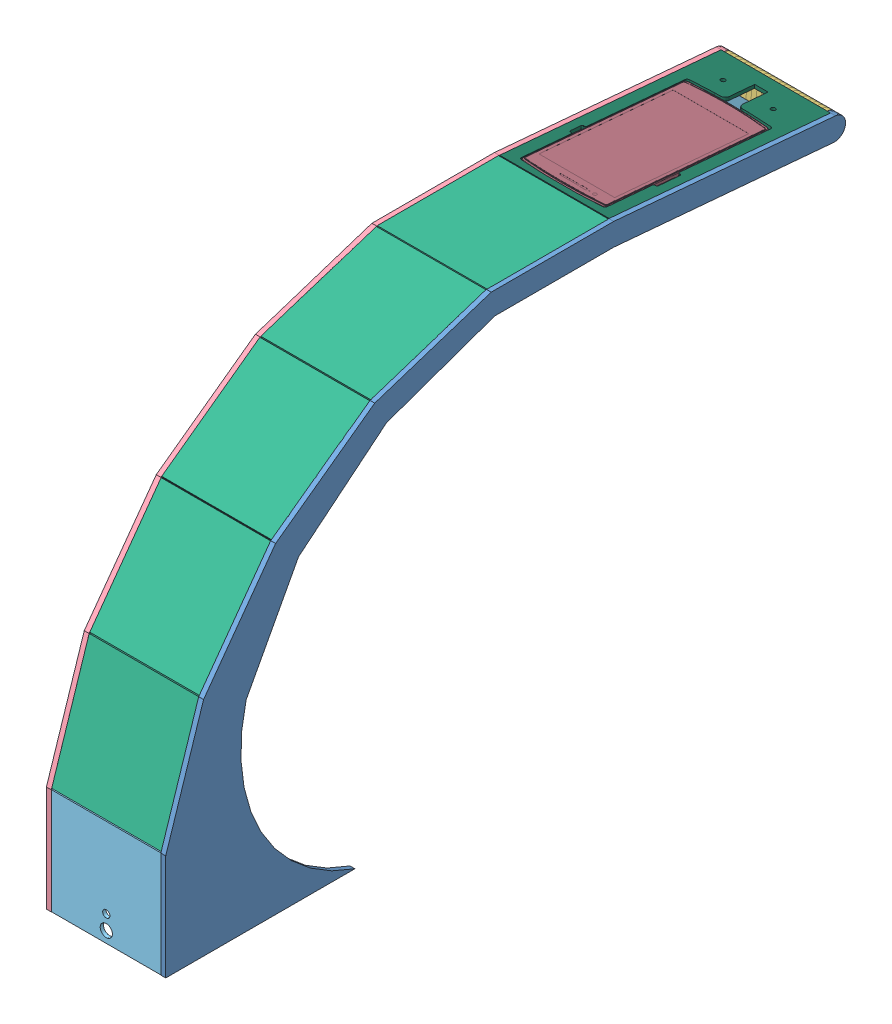
SolidWorks assembly Assem1, configuration Default. Lengths in mm.
Overall size (107.2 389.46 611.71).
44 component instances, 16 part files, 66 mates.
Components (placement in the parent):
- Outer Edge v2-1: Outer Edge v2 [Default] at (211.152 225.8443 792.324) size (7.4 387.43 610.87)
- phone support-1: phone support [Default] at (152.1683 492.2276 185.5195) x (1 0 0) z (0 0.087156 0.996195) size (98.5 3.2 10)
- phone support-2: phone support [Default] at (152.1683 496.7484 240.6352) x (1 0 0) z (0 0.087156 0.996195) size (98.5 3.2 10)
- phone support-3: phone support [Default] at (152.1683 504.6448 330.8905) x (1 0 0) z (0 0.087156 0.996195) size (98.5 3.2 10)
- Rounded piece v1-1: Rounded piece v1 [Default] at (203.752 493.2491 178.8372) x (-1 0 0) z (0 -0.087156 -0.996195) size (4.4 20 20)
- Rounded piece v1-2: Rounded piece v1 [Default] at (199.352 493.2491 178.8372) x (-1 0 0) z (0 -0.087156 -0.996195) size (4.4 20 20)
- Rounded piece v1-3: Rounded piece v1 [Default] at (194.952 493.2491 178.8372) x (-1 0 0) z (0 -0.087156 -0.996195) size (4.4 20 20)
- Rounded piece v1-4: Rounded piece v1 [Default] at (190.552 493.2491 178.8372) x (-1 0 0) z (0 -0.087156 -0.996195) size (4.4 20 20)
- Rounded piece v1-5: Rounded piece v1 [Default] at (186.152 493.2491 178.8372) x (-1 0 0) z (0 -0.087156 -0.996195) size (4.4 20 20)
- Rounded piece v1-6: Rounded piece v1 [Default] at (181.752 493.2491 178.8372) x (-1 0 0) z (0 -0.087156 -0.996195) size (4.4 20 20)
- Rounded piece v1-7: Rounded piece v1 [Default] at (177.352 493.2491 178.8372) x (-1 0 0) z (0 -0.087156 -0.996195) size (4.4 20 20)
- Rounded piece v1-8: Rounded piece v1 [Default] at (172.952 493.2491 178.8372) x (-1 0 0) z (0 -0.087156 -0.996195) size (4.4 20 20)
- Rounded piece v1-9: Rounded piece v1 [Default] at (168.552 493.2491 178.8372) x (-1 0 0) z (0 -0.087156 -0.996195) size (4.4 20 20)
- Rounded piece v1-10: Rounded piece v1 [Default] at (164.152 493.2491 178.8372) x (-1 0 0) z (0 -0.087156 -0.996195) size (4.4 20 20)
- Rounded piece v1-11: Rounded piece v1 [Default] at (159.752 493.2491 178.8372) x (-1 0 0) z (0 -0.087156 -0.996195) size (4.4 20 20)
- Rounded piece v1-12: Rounded piece v1 [Default] at (155.352 493.2491 178.8372) x (-1 0 0) z (0 -0.087156 -0.996195) size (4.4 20 20)
- Rounded piece v1-13: Rounded piece v1 [Default] at (150.952 493.2491 178.8372) x (-1 0 0) z (0 -0.087156 -0.996195) size (4.4 20 20)
- Rounded piece v1-14: Rounded piece v1 [Default] at (146.552 493.2491 178.8372) x (-1 0 0) z (0 -0.087156 -0.996195) size (4.4 20 20)
- Rounded piece v1-15: Rounded piece v1 [Default] at (142.152 493.2491 178.8372) x (-1 0 0) z (0 -0.087156 -0.996195) size (4.4 20 20)
- Rounded piece v1-16: Rounded piece v1 [Default] at (137.752 493.2491 178.8372) x (-1 0 0) z (0 -0.087156 -0.996195) size (4.4 20 20)
- Rounded piece v1-17: Rounded piece v1 [Default] at (133.352 493.2491 178.8372) x (-1 0 0) z (0 -0.087156 -0.996195) size (4.4 20 20)
- Rounded piece v1-18: Rounded piece v1 [Default] at (128.952 493.2491 178.8372) x (-1 0 0) z (0 -0.087156 -0.996195) size (4.4 20 20)
- Rounded piece v1-19: Rounded piece v1 [Default] at (124.552 493.2491 178.8372) x (-1 0 0) z (0 -0.087156 -0.996195) size (4.4 20 20)
- Rounded piece v1-20: Rounded piece v1 [Default] at (120.152 493.2491 178.8372) x (-1 0 0) z (0 -0.087156 -0.996195) size (4.4 20 20)
- Rounded piece v1-21: Rounded piece v1 [Default] at (115.752 493.2491 178.8372) x (-1 0 0) z (0 -0.087156 -0.996195) size (4.4 20 20)
- MirrorOuter Edge v2-5: MirrorOuter Edge v2 [Default] at (103.952 225.8443 792.324) x (-1 0 0) z (0 0 -1) size (7.4 387.43 610.87)
- top 1-1: top 1 [Default] at (128.85 126.9295 779.5123) x (0 -1 0) z (1 0 0) size (95 3 98.8)
- top 2-3-4-5-6-1: top 2-3-4-5-6 [Default] at (186.254 289.8492 756.5132) x (0 -0.951057 0.309017) z (-1 0 0) size (109 3 98.8)
- top 2-3-4-5-6-2: top 2-3-4-5-6 [Default] at (186.254 369.4632 719.1072) x (0 0.809017 -0.587785) z (-1 0 0) size (109 3 98.8)
- top 2-3-4-5-6-3: top 2-3-4-5-6 [Default] at (186.254 458.0212 626.2249) x (0 -0.587785 0.809017) z (-1 0 0) size (109 3 98.8)
- top 2-3-4-5-6-4: top 2-3-4-5-6 [Default] at (128.85 497.6699 548.2656) x (0 0.309017 -0.951057) z (1 0 0) size (109 3 98.8)
- top 2-3-4-5-6-5: top 2-3-4-5-6 [Default] at (128.85 517.6422 442.4332) x (0 0 -1) z (1 0 0) size (109 3 98.8)
- bottom 1-2: bottom 1 [Default] at (128.85 175.7778 702.9849) x (0 0.937746 0.347321) z (1 0 0) size (102 3 98.8)
- bottom 2-2: bottom 2 [Default] at (186.254 273.9501 717.8573) x (0 0.982743 -0.184975) z (-1 0 0) size (85.2 3 98.8)
- bottom 3-1: bottom 3 [Default] at (128.85 363.8422 683.7778) x (0 -0.880634 0.473798) z (1 0 0) size (99.7 3 98.8)
- bottom 4-1: bottom 4 [Default] at (128.85 429.4876 625.9213) x (0 0.633634 -0.773633) z (1 0 0) size (102.06 3 98.8)
- bottom 5-1: bottom 5 [Default] at (128.85 480.8727 539.4632) x (0 0.33437 -0.942442) z (1 0 0) size (103 3 98.8)
- bottom 6-1: bottom 6 [Default] at (186.254 500.5527 421.526) x (0 -0.000295 1) z (-1 0 0) size (106.88 3 98.8)
- ONEPLUSONE.catpart-1: ONEPLUSONE.catpart [Default] at (157.552 507.1829 218.7748) x (-1 0 0) z (0 0.996195 -0.087156) size (76.5 179.63 10.19)
- bottom 7-1: bottom 7 [Default] at (136.6559 495.3125 317.1592) x (0 -0.087156 -0.996195) z (1 0 0) size (198.26 3 98.8)
- top phone insert-1: top phone insert [Default] at (134.9798 513.2564 327.2058) x (0 -0.087156 -0.996195) z (1 0 0) size (199.69 3 98.8)
- phone support-4: phone support [Default] at (152.2683 163.411 758.2766) size (98.5 3.2 10)
- phone support-5: phone support [Default] at (152.2683 221.787 733.2489) x (1 0 0) z (0 0.937746 0.347321) size (98.5 3.2 10)
- Weight Container v1-1: Weight Container v1 [Default] at (194.352 213.6689 753.652) x (0 0 1) z (0 -1 0) size (62 83 163.96)
Mates (geometry in assembly coordinates):
- Coincident3: coincident: plane of Outer Edge v2-1 through (206.752 493.2491 178.8372) normal (-1 0 0); plane of phone support-1 through (206.752 494.4072 173.7168) normal (1 0 0)
- Width1: width: plane of phone support-1 through (108.252 495.2788 183.6787) normal (0 0.087156 0.996195); plane of phone support-1 through (108.252 494.4072 173.7168) normal (0 -0.087156 -0.996195); plane of Outer Edge v2-1 through (203.752 495.5041 183.9601) normal (0 -0.087156 -0.996195); plane of Outer Edge v2-1 through (203.752 494.5803 173.4005) normal (0 0.087156 0.996195)
- Width2: width: plane of phone support-1 through (152.1683 495.4154 185.2406) normal (0 0.996195 -0.087156); plane of phone support-1 through (152.1683 492.2276 185.5195) normal (0 -0.996195 0.087156); plane of Outer Edge v2-1 through (203.752 494.5803 173.4005) normal (0 -0.996195 0.087156); plane of Outer Edge v2-1 through (203.752 490.994 173.7142) normal (0 0.996195 -0.087156)
- Coincident6: coincident: plane of Outer Edge v2-1 through (206.752 493.2491 178.8372) normal (-1 0 0); plane of phone support-2 through (206.752 498.9281 228.8325) normal (1 0 0)
- Width3: width: plane of phone support-2 through (108.252 499.7996 238.7944) normal (0 0.087156 0.996195); plane of phone support-2 through (108.252 498.9281 228.8325) normal (0 -0.087156 -0.996195); plane of Outer Edge v2-1 through (203.752 500.025 239.0759) normal (0 -0.087156 -0.996195); plane of Outer Edge v2-1 through (203.752 499.1012 228.5162) normal (0 0.087156 0.996195)
- Width4: width: plane of phone support-2 through (152.1683 499.9363 240.3563) normal (0 0.996195 -0.087156); plane of phone support-2 through (152.1683 496.7484 240.6352) normal (0 -0.996195 0.087156); plane of Outer Edge v2-1 through (203.752 499.1012 228.5162) normal (0 -0.996195 0.087156); plane of Outer Edge v2-1 through (203.752 495.5149 228.83) normal (0 0.996195 -0.087156)
- Coincident7: coincident: plane of Outer Edge v2-1 through (206.752 493.2491 178.8372) normal (-1 0 0); plane of phone support-3 through (206.752 506.8244 319.0877) normal (1 0 0)
- Width5: width: plane of phone support-3 through (108.252 506.8244 319.0877) normal (0 -0.087156 -0.996195); plane of phone support-3 through (108.252 507.6959 329.0497) normal (0 0.087156 0.996195); plane of Outer Edge v2-1 through (203.752 507.9213 329.3311) normal (0 -0.087156 -0.996195); plane of Outer Edge v2-1 through (203.752 506.9975 318.7714) normal (0 0.087156 0.996195)
- Width6: width: plane of phone support-3 through (152.1683 507.8326 330.6116) normal (0 0.996195 -0.087156); plane of phone support-3 through (152.1683 504.6448 330.8905) normal (0 -0.996195 0.087156); plane of Outer Edge v2-1 through (203.752 503.4112 319.0852) normal (0 0.996195 -0.087156); plane of Outer Edge v2-1 through (203.752 506.9975 318.7714) normal (0 -0.996195 0.087156)
- Coincident8: coincident: plane of Outer Edge v2-1 through (203.752 493.2491 178.8372) normal (-1 0 0); plane of Rounded piece v1-1 through (203.752 493.2491 178.8372) normal (1 0 0)
- Width7: width: plane of phone support-1 through (152.1683 495.4154 185.2406) normal (0 0.996195 -0.087156); plane of phone support-1 through (152.1683 492.2276 185.5195) normal (0 -0.996195 0.087156); plane of Rounded piece v1-1 through (199.352 494.7621 173.1838) normal (0 -0.996195 0.087156); plane of Rounded piece v1-1 through (199.352 490.7773 173.5324) normal (0 0.996195 -0.087156)
- Width8: width: plane of phone support-1 through (108.252 494.4072 173.7168) normal (0 -0.087156 -0.996195); plane of phone support-1 through (108.252 495.2788 183.6787) normal (0 0.087156 0.996195); plane of Rounded piece v1-1 through (199.352 494.7621 173.1838) normal (0 0.087156 0.996195); plane of Rounded piece v1-1 through (199.352 495.7208 184.142) normal (0 -0.087156 -0.996195)
- Width9: width: plane of MirrorOuter Edge v2-5 through (108.352 493.2491 178.8372) normal (1 0 0); plane of Outer Edge v2-1 through (206.752 493.2491 178.8372) normal (-1 0 0); plane of top 1-1 through (108.152 228.211 776.5123) normal (-1 0 0); plane of top 1-1 through (206.952 228.211 776.5123) normal (1 0 0)
- Coincident10: coincident: plane of top 1-1 through (108.152 133.211 776.5123) normal (0 -1 0); line of MirrorOuter Edge v2-5 through (108.352 133.211 779.7088) axis (0 0 -1)
- Width10: width: plane of MirrorOuter Edge v2-5 through (108.352 493.2491 178.8372) normal (1 0 0); plane of Outer Edge v2-1 through (206.752 493.2491 178.8372) normal (-1 0 0); plane of top 2-3-4-5-6-1 through (108.152 332.8905 745.6826) normal (-1 0 0); plane of top 2-3-4-5-6-1 through (206.952 332.8905 745.6826) normal (1 0 0)
- Coincident11: coincident: plane of MirrorOuter Edge v2-5 through (111.352 331.5022 742.9793) normal (0 0.309017 0.951057); plane of top 2-3-4-5-6-1 through (186.254 289.8492 756.5132) normal (0 -0.309017 -0.951057)
- Coincident13: coincident: plane of MirrorOuter Edge v2-5 through (111.352 228.2983 776.5123) normal (0 0 1); plane of top 1-1 through (128.85 126.9295 776.5123) normal (0 0 -1)
- Coincident14: coincident: point of MirrorOuter Edge v2-5; plane of top 2-3-4-5-6-1 through (206.952 229.2253 779.3654) normal (0 -0.951057 0.309017)
- Width11: width: plane of MirrorOuter Edge v2-5 through (108.352 493.2491 178.8372) normal (1 0 0); plane of Outer Edge v2-1 through (206.752 493.2491 178.8372) normal (-1 0 0); plane of top 2-3-4-5-6-2 through (108.152 331.8753 742.7082) normal (-1 0 0); plane of top 2-3-4-5-6-2 through (206.952 331.8753 742.7082) normal (1 0 0)
- Coincident15: coincident: plane of MirrorOuter Edge v2-5 through (111.352 419.7772 678.8438) normal (0 0.587785 0.809017); plane of top 2-3-4-5-6-2 through (186.254 367.6999 716.6801) normal (0 -0.587785 -0.809017)
- Coincident18: coincident: line of top 2-3-4-5-6-1 through (206.952 331.9634 742.8294) axis (-1 0 0); plane of top 2-3-4-5-6-2 through (206.952 331.8753 742.7082) normal (0 -0.809017 0.587785)
- Width12: width: plane of MirrorOuter Edge v2-5 through (103.952 493.2491 178.8372) normal (-1 0 0); plane of Outer Edge v2-1 through (211.152 493.2491 178.8372) normal (1 0 0); plane of top 2-3-4-5-6-3 through (206.952 486.4763 592.1637) normal (1 0 0); plane of top 2-3-4-5-6-3 through (108.152 486.4763 592.1637) normal (-1 0 0)
- Coincident19: coincident: plane of MirrorOuter Edge v2-5 through (108.352 421.9331 680.9997) normal (0 0.809017 0.587785); plane of top 2-3-4-5-6-3 through (186.254 460.4482 627.9883) normal (0 0.809017 0.587785)
- Coincident20: coincident: line of top 2-3-4-5-6-2 through (108.152 420.0582 678.6396) axis (1 0 0); plane of top 2-3-4-5-6-3 through (206.952 422.4077 680.3466) normal (0 -0.587785 0.809017)
- Width13: width: plane of Outer Edge v2-1 through (211.152 493.2491 178.8372) normal (1 0 0); plane of MirrorOuter Edge v2-5 through (103.952 493.2491 178.8372) normal (-1 0 0); plane of top 2-3-4-5-6-4 through (108.152 486.8393 591.3069) normal (-1 0 0); plane of top 2-3-4-5-6-4 through (206.952 486.8393 591.3069) normal (1 0 0)
- Coincident21: coincident: plane of MirrorOuter Edge v2-5 through (108.352 486.6294 591.953) normal (0 0.951057 0.309017); plane of top 2-3-4-5-6-4 through (128.85 500.523 549.1927) normal (0 0.951057 0.309017)
- Coincident22: coincident: line of top 2-3-4-5-6-3 through (206.952 484.0492 590.4004) axis (-1 0 0); plane of top 2-3-4-5-6-4 through (108.152 486.8393 591.3069) normal (0 -0.309017 0.951057)
- Width14: width: plane of Outer Edge v2-1 through (211.152 493.2491 178.8372) normal (1 0 0); plane of MirrorOuter Edge v2-5 through (103.952 493.2491 178.8372) normal (-1 0 0); plane of top 2-3-4-5-6-5 through (108.152 520.6422 486.7147) normal (-1 0 0); plane of top 2-3-4-5-6-5 through (206.952 520.6422 486.7147) normal (1 0 0)
- Coincident23: coincident: plane of Outer Edge v2-1 through (206.752 520.6422 487.2723) normal (0 1 0); plane of top 2-3-4-5-6-5 through (128.85 520.6422 442.4332) normal (0 1 0)
- Coincident25: coincident: line of top 2-3-4-5-6-4 through (206.952 517.669 486.7147) axis (-1 0 0); plane of top 2-3-4-5-6-5 through (108.152 520.6422 486.7147) normal (0 0 1)
- Width16: width: plane of Outer Edge v2-1 through (211.152 493.2491 178.8372) normal (1 0 0); plane of MirrorOuter Edge v2-5 through (103.952 493.2491 178.8372) normal (-1 0 0); plane of bottom 1-2 through (108.152 133.211 690.4182) normal (-1 0 0); plane of bottom 1-2 through (206.952 133.211 690.4182) normal (1 0 0)
- Coincident26: coincident: plane of Outer Edge v2-1 through (203.752 133.211 690.4182) normal (0 0.347321 -0.937746); plane of bottom 1-2 through (128.85 174.7359 705.7981) normal (0 -0.347321 0.937746)
- Coincident27: coincident: line of MirrorOuter Edge v2-5 through (111.352 133.211 690.4182) axis (-1 0 0); plane of bottom 1-2 through (108.152 133.211 690.4182) normal (0 -0.937746 -0.347321)
- Width20: width: plane of Outer Edge v2-1 through (211.152 493.2491 178.8372) normal (1 0 0); plane of MirrorOuter Edge v2-5 through (103.952 493.2491 178.8372) normal (-1 0 0); plane of bottom 2-2 through (206.952 229.8778 723.1) normal (1 0 0); plane of bottom 2-2 through (108.152 229.8778 723.1) normal (-1 0 0)
- Coincident31: coincident: plane of MirrorOuter Edge v2-5 through (111.352 229.7546 726.1759) normal (0 -0.184975 -0.982743); plane of bottom 2-2 through (186.254 273.9501 717.8573) normal (0 0.184975 0.982743)
- Coincident36: coincident: plane of bottom 1-2 through (108.152 228.8611 725.845) normal (0 0.937746 0.347321); line of bottom 2-2 through (206.952 229.8778 723.1) axis (-1 0 0)
- Width21: width: plane of Outer Edge v2-1 through (211.152 493.2491 178.8372) normal (1 0 0); plane of MirrorOuter Edge v2-5 through (103.952 493.2491 178.8372) normal (-1 0 0); plane of bottom 3-1 through (108.152 401.4167 660.1554) normal (-1 0 0); plane of bottom 3-1 through (206.952 401.4167 660.1554) normal (1 0 0)
- Coincident37: coincident: plane of bottom 3-1 through (128.85 363.8422 683.7778) normal (0 0.473798 0.880634); plane of MirrorOuter Edge v2-5 through (111.352 314.7856 710.1711) normal (0 -0.473798 -0.880634)
- Coincident38: coincident: plane of bottom 2-2 through (206.952 313.6075 707.3402) normal (0 0.982743 -0.184975); line of bottom 3-1 through (206.952 313.6175 707.393) axis (-1 0 0)
- Width22: width: plane of Outer Edge v2-1 through (211.152 493.2491 178.8372) normal (1 0 0); plane of MirrorOuter Edge v2-5 through (103.952 493.2491 178.8372) normal (-1 0 0); plane of bottom 4-1 through (108.152 403.7503 662.0799) normal (-1 0 0); plane of bottom 4-1 through (206.952 403.7503 662.0799) normal (1 0 0)
- Coincident39: coincident: plane of bottom 3-1 through (108.152 401.4167 660.1554) normal (0 0.880634 -0.473798); line of bottom 4-1 through (108.152 401.4294 660.179) axis (1 0 0)
- Coincident40: coincident: plane of MirrorOuter Edge v2-5 through (111.352 403.4184 662.485) normal (0 -0.773633 -0.633634); plane of bottom 4-1 through (128.85 431.8085 627.8222) normal (0 0.773633 0.633634)
- Width23: width: plane of Outer Edge v2-1 through (211.152 493.2491 178.8372) normal (1 0 0); plane of MirrorOuter Edge v2-5 through (103.952 493.2491 178.8372) normal (-1 0 0); plane of bottom 5-1 through (108.152 468.8936 582.1991) normal (-1 0 0); plane of bottom 5-1 through (206.952 468.8936 582.1991) normal (1 0 0)
- Coincident41: coincident: plane of bottom 4-1 through (108.152 468.4189 583.1229) normal (0 0.633634 -0.773633); line of bottom 5-1 through (108.152 466.0663 581.196) axis (1 0 0)
- Coincident42: coincident: plane of Outer Edge v2-1 through (203.752 503.5341 484.5627) normal (0 -0.942442 -0.33437); plane of bottom 5-1 through (128.85 483.7 540.4663) normal (0 0.942442 0.33437)
- Width24: width: plane of Outer Edge v2-1 through (211.152 493.2491 178.8372) normal (1 0 0); plane of MirrorOuter Edge v2-5 through (103.952 493.2491 178.8372) normal (-1 0 0); plane of bottom 6-1 through (108.152 503.5658 377.2454) normal (-1 0 0); plane of bottom 6-1 through (206.952 503.5658 377.2454) normal (1 0 0)
- Coincident43: coincident: line of bottom 5-1 through (206.952 500.5064 484.1245) axis (-1 0 0); plane of bottom 6-1 through (206.952 503.5343 484.1254) normal (0 -0.000295 1)
- Coincident44: coincident: plane of Outer Edge v2-1 through (203.752 503.5658 377.074) normal (0 -1 -0.000295); plane of bottom 6-1 through (186.254 503.5527 421.5269) normal (0 1 0.000295)
- Width25: width: plane of Outer Edge v2-1 through (211.152 493.2491 178.8372) normal (1 0 0); plane of MirrorOuter Edge v2-5 through (103.952 493.2491 178.8372) normal (-1 0 0); plane of bottom 7-1 through (108.152 503.5808 377.2454) normal (-1 0 0); plane of bottom 7-1 through (206.952 503.5808 377.2454) normal (1 0 0)
- Coincident45: coincident: plane of bottom 6-1 through (206.952 503.5658 377.2454) normal (0 0.000295 -1); line of bottom 7-1 through (108.152 503.5808 377.2454) axis (1 0 0)
- Coincident46: coincident: plane of MirrorOuter Edge v2-5 through (111.352 486.2757 179.4473) normal (0 -0.996195 0.087156); plane of bottom 7-1 through (136.6559 498.3011 316.8977) normal (0 0.996195 -0.087156)
- Coincident47: coincident: plane of phone support-3 through (152.1683 507.8326 330.6116) normal (0 0.996195 -0.087156); plane of ONEPLUSONE.catpart-1 through (140.5654 498.1175 219.5679) normal (0 -0.996195 0.087156)
- Width26: width: plane of Outer Edge v2-1 through (211.152 493.2491 178.8372) normal (1 0 0); plane of MirrorOuter Edge v2-5 through (103.952 493.2491 178.8372) normal (-1 0 0); plane of top phone insert-1 through (108.152 520.6152 376.8958) normal (-1 0 0); plane of top phone insert-1 through (206.952 520.6152 376.8958) normal (1 0 0)
- Coincident48: coincident: plane of Outer Edge v2-1 through (203.752 500.2224 178.2271) normal (0 0.996195 -0.087156); plane of top phone insert-1 through (134.9798 513.2564 327.2058) normal (0 -0.996195 0.087156)
- Coincident49: coincident: plane of Outer Edge v2-1 through (203.752 503.211 177.9656) normal (0 0.087156 0.996195); plane of top phone insert-1 through (108.152 503.211 177.9656) normal (0 -0.087156 -0.996195)
- Width27: width: plane of top phone insert-1 through (195.952 506.9846 221.0976) normal (-1 0 0); plane of top phone insert-1 through (119.152 514.6851 309.1147) normal (1 0 0); plane of ONEPLUSONE.catpart-1 through (119.552 520.14 366.8757) normal (-1 0 0); plane of ONEPLUSONE.catpart-1 through (195.552 520.14 366.8757) normal (1 0 0)
- Tangent1: tangent: cylinder of ONEPLUSONE.catpart-1 through (157.552 475.1316 -89.6304) axis (0 -0.996195 0.087156) radius 463.025; plane of top phone insert-1 through (172.6793 520.1192 371.2274) normal (0 -0.087156 -0.996195)
- Width28: width: plane of phone support-4 through (152.2683 163.411 758.2766) normal (0 -1 0); plane of phone support-4 through (152.2683 166.611 758.2766) normal (0 1 0); plane of MirrorOuter Edge v2-5 through (111.352 163.211 746.4088) normal (0 1 0); plane of MirrorOuter Edge v2-5 through (111.352 166.811 746.4088) normal (0 -1 0)
- Width29: width: plane of phone support-4 through (108.352 166.611 756.7088) normal (0 0 1); plane of phone support-4 through (108.352 166.611 746.7088) normal (0 0 -1); plane of MirrorOuter Edge v2-5 through (111.352 166.811 746.4088) normal (0 0 1); plane of MirrorOuter Edge v2-5 through (111.352 166.811 757.0088) normal (0 0 -1)
- Coincident50: coincident: plane of MirrorOuter Edge v2-5 through (108.352 493.2491 178.8372) normal (1 0 0); plane of phone support-4 through (108.352 166.611 746.7088) normal (-1 0 0)
- Width30: width: plane of phone support-5 through (152.2683 222.8984 730.2481) normal (0 0.347321 -0.937746); plane of phone support-5 through (152.2683 221.787 733.2489) normal (0 -0.347321 0.937746); plane of MirrorOuter Edge v2-5 through (111.352 221.779 729.6202) normal (0 -0.347321 0.937746); plane of MirrorOuter Edge v2-5 through (111.352 220.5286 732.9961) normal (0 0.347321 -0.937746)
- Width31: width: plane of phone support-5 through (108.352 221.4282 729.7036) normal (0 0.937746 0.347321); plane of phone support-5 through (108.352 212.0507 726.2304) normal (0 -0.937746 -0.347321); plane of MirrorOuter Edge v2-5 through (111.352 221.779 729.6202) normal (0 -0.937746 -0.347321); plane of MirrorOuter Edge v2-5 through (111.352 211.8389 725.9386) normal (0 0.937746 0.347321)
- Coincident51: coincident: plane of MirrorOuter Edge v2-5 through (108.352 493.2491 178.8372) normal (1 0 0); plane of phone support-5 through (108.352 212.0507 726.2304) normal (-1 0 0)
- Coincident52: coincident: plane of MirrorOuter Edge v2-5 through (111.352 493.2491 178.8372) normal (1 0 0); plane of Weight Container v1-1 through (111.352 213.6689 753.652) normal (-1 0 0)
- Coincident53: coincident: plane of phone support-4 through (152.2683 166.611 758.2766) normal (0 1 0); plane of Weight Container v1-1 through (113.352 166.611 776.6543) normal (0 -1 0)
- Coincident54: coincident: plane of top 2-3-4-5-6-1 through (186.254 289.8492 756.5132) normal (0 -0.309017 -0.951057); plane of Weight Container v1-1 through (113.352 330.5751 743.2805) normal (0 0.309017 0.951057)
